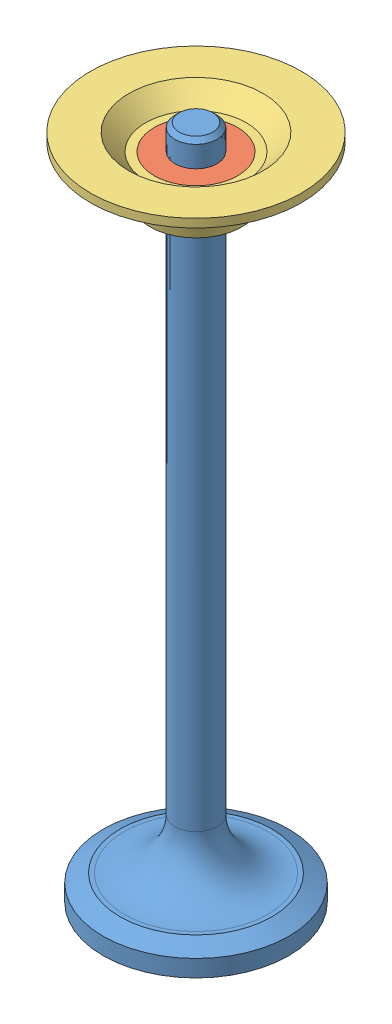
SolidWorks assembly Assem1, configuration Default. Lengths in mm.
Overall size (34.09 80 34.09).
3 component instances, 3 part files, 5 mates.
Components (placement in the parent):
- Valve-1: Valve [Default] at origin size (22 80 22)
- Valve Retainer Inner-1: Valve Retainer Inner [Default] at (0 77 0) size (9.9 4.99 9.9)
- Valve Retainer Outer-1: Valve Retainer Outer [Default] at (0 77 0) x (0.494141 0 0.869382) z (-0.869382 0 0.494141) size (25 7 25)
Mates (geometry in assembly coordinates):
- Coincident1: coordinate: point of Valve-1
- Coincident5: coincident anti-aligned: plane of Valve-1 through (2.5 77 0) normal (0 -1 0); plane of Valve Retainer Inner-1 through (4.95 77 0) normal (0 1 0)
- Concentric5: concentric anti-aligned: cylinder of Valve-1 through (0 0 0) axis (0 -1 0) radius 1.5; cylinder of Valve Retainer Inner-1 through (0 77 0) axis (0 1 0) radius 1.95
- Concentric7: concentric aligned: cone of Valve Retainer Inner-1 through (0 72.0112 0) axis (0 -1 0); cone of Valve Retainer Outer-1 through (0 77 0) axis (0 -1 0)
- Coincident6: coincident aligned: plane of Valve Retainer Inner-1 through (4.95 77 0) normal (0 1 0); plane of Valve Retainer Outer-1 through (2.446 77 4.3034) normal (0 1 0)
